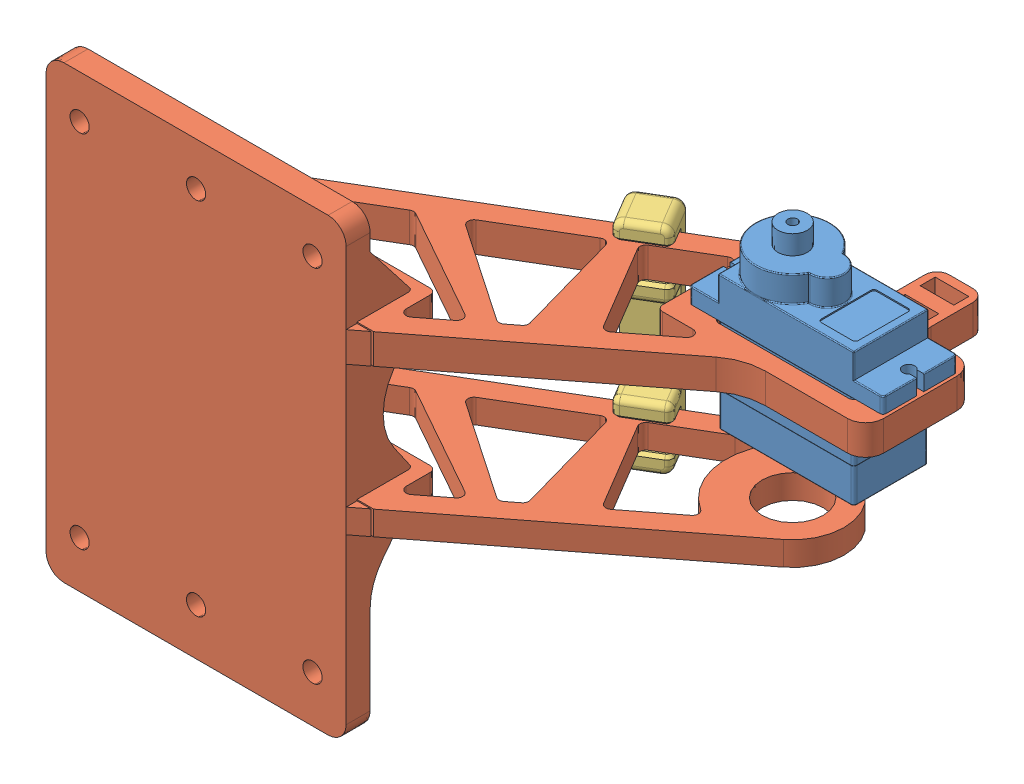
SolidWorks assembly _LIFT, configuration Default. Lengths in mm.
Overall size (107.58 75 58.15).
5 component instances, 4 part files, 8 mates.
Components (placement in the parent):
- microservoAssembly-1: microservoAssembly [Default] at origin size (38.45 31.3 12.5)
  - microservoSG90-1: microservoSG90 [Default] at (7.8094 3.3655 26.0766) size (32.3 29.8 12.5)
  - microservoArm-1: microservoArm [A2] at (2.7094 34.6655 26.0766) x (-1 0 0.000751) z (0.000751 0 1) size (34.4 3.9 7) (hidden)
- Part9^_LIFT-1: Part9^_LIFT [Default] at (7.8094 18.9655 26.0766) x (-1 0 0) z (0 -1 0) size (107.58 58.15 75) (virtual)
- rib^_LIFT-1: rib^_LIFT [Default] at (-0.7524 18.9655 11.6699) x (-0.85965 0 0.510884) z (-0.510884 0 -0.85965) size (7.5 36 7) (virtual)
Mates (geometry in assembly coordinates):
- InPlace1: in place: plane of microservoAssembly-1/microservoSG90-1 through (7.8094 18.9655 26.0766) normal (0 -1 0); plane of ? through (0 18.9655 0) normal (0 -1 0); moOrthogonalPlaneRef_w of microservoAssembly-1/microservoSG90-1 through (7.8094 18.9655 26.0766) normal (0 -1 0); plane of ? through (0 18.9655 0) normal (0 0 -1); plane of microservoAssembly-1/microservoSG90-1 through (7.8094 18.9655 26.0766) normal (0 -1 0); plane of ? through (0 18.9655 0) normal (-1 0 0); plane of microservoAssembly-1/microservoSG90-1 through (7.8094 18.9655 26.0766) normal (0 -1 0); unknown of Part9^_LIFT-1
- Coincident2: coincident aligned: plane of ?; plane of ?
- Coincident3: coincident aligned: moOrthogonalPlaneRef_w of microservoAssembly-1/microservoSG90-1 through (7.8094 18.9655 26.0766) normal (0 0 -1); plane of Part9^_LIFT-1 through (7.8094 18.9655 26.0766) normal (0 0 -1)
- Coincident4: coincident anti-aligned: moOrthogonalPlaneRef_w of microservoAssembly-1/microservoSG90-1 through (7.8094 18.9655 26.0766) normal (1 0 0); plane of Part9^_LIFT-1 through (7.8094 18.9655 26.0766) normal (-1 0 0)
- InPlace2: in place: plane of Part9^_LIFT-1 through (-0.7524 -6.6345 11.6699) normal (-0.510884 0 -0.85965); plane of ? through (4.9288 0 8.2936) normal (-0.510884 0 -0.85965); plane of Part9^_LIFT-1 through (-0.7524 -6.6345 11.6699) normal (-0.510884 0 -0.85965); plane of ? through (4.9288 0 8.2936) normal (0 1 0); plane of Part9^_LIFT-1 through (-0.7524 -6.6345 11.6699) normal (-0.510884 0 -0.85965); plane of ? through (4.9288 0 8.2936) normal (-0.85965 0 0.510884); plane of Part9^_LIFT-1 through (-0.7524 -6.6345 11.6699) normal (-0.510884 0 -0.85965); unknown of rib^_LIFT-1
- Coincident1: coincident aligned: plane of ?; plane of ?
- Coincident2: coincident aligned: moOrthogonalPlaneRef_w of Part9^_LIFT-1 through (-0.7524 18.9655 11.6699) normal (0 1 0); plane of Part1^_LIFT-1 through (-0.7524 18.9655 11.6699) normal (0 1 0)
- Coincident3: coincident anti-aligned: moOrthogonalPlaneRef_w of Part9^_LIFT-1 through (-0.7524 18.9655 11.6699) normal (0.85965 0 -0.510884); plane of Part1^_LIFT-1 through (-0.7524 18.9655 11.6699) normal (-0.85965 0 0.510884)
